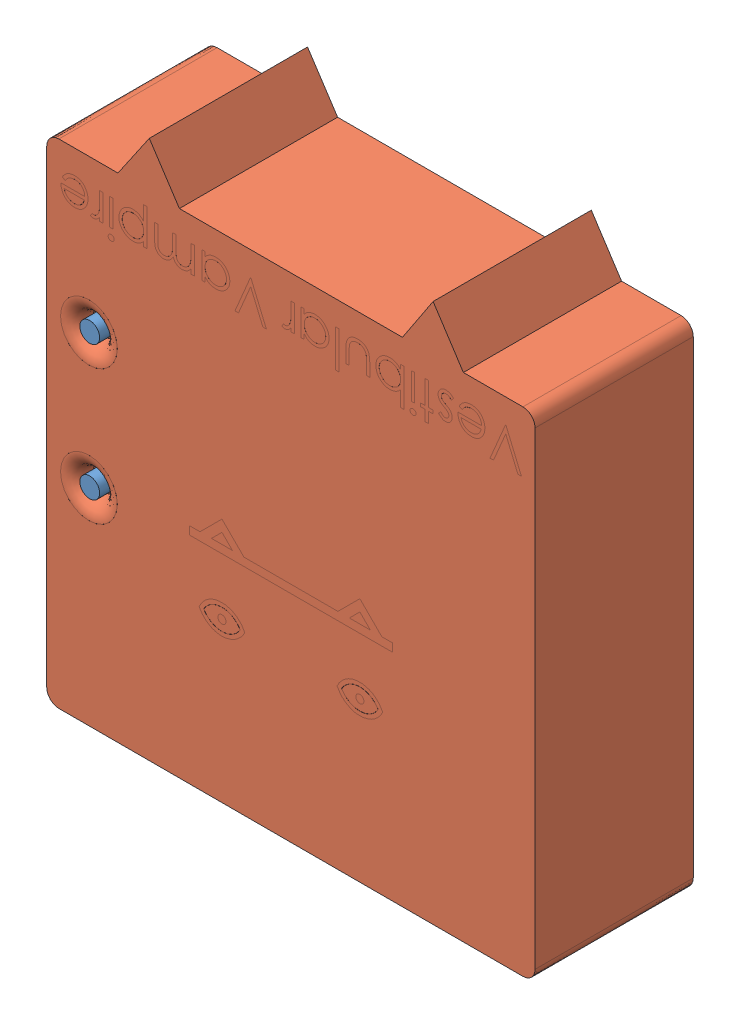
SolidWorks assembly vestibular_vampire, configuration Default. Lengths in mm.
Overall size (60.2 66.52 19.5).
2 component instances, 2 part files, 4 mates.
Components (placement in the parent):
- vestibular_vampire_v1.0_3d_model-1: vestibular_vampire_v1.0_3d_model [Default] at (-83.4995 -0.066 6.5928) size (54.8 61.2 11.11)
- housing-1: housing [Default] at (-83.4995 -0.066 5.207) x (-1 0 0) z (0 0 -1) size (60.2 66.52 19.5)
Mates (geometry in assembly coordinates):
- InPlace1: in place: plane of vestibular_vampire_v1.0_3d_model-1 through (-53.496 28.6789 5.207) normal (0 0 -1); plane of ? through (0 0 5.207) normal (0 0 -1); moOrthogonalPlaneRef_w of vestibular_vampire_v1.0_3d_model-1 through (-53.496 28.6789 5.207) normal (0 0 -1); plane of ? through (0 0 5.207) normal (0 1 0); plane of vestibular_vampire_v1.0_3d_model-1 through (-53.496 28.6789 5.207) normal (0 0 -1); plane of ? through (0 0 5.207) normal (-1 0 0); plane of vestibular_vampire_v1.0_3d_model-1 through (-53.496 28.6789 5.207) normal (0 0 -1); unknown of housing-1
- Coincident1: coincident aligned: plane of vestibular_vampire_v1.0_3d_model-1; plane of housing-1
- Coincident2: coincident aligned: moOrthogonalPlaneRef_w of vestibular_vampire_v1.0_3d_model-1 through (-83.4995 -0.066 5.207) normal (0 1 0); plane of housing-1 through (-83.4995 -0.066 5.207) normal (0 1 0)
- Coincident3: coincident anti-aligned: moOrthogonalPlaneRef_w of vestibular_vampire_v1.0_3d_model-1 through (-83.4995 -0.066 5.207) normal (1 0 0); plane of housing-1 through (-83.4995 -0.066 5.207) normal (-1 0 0)
